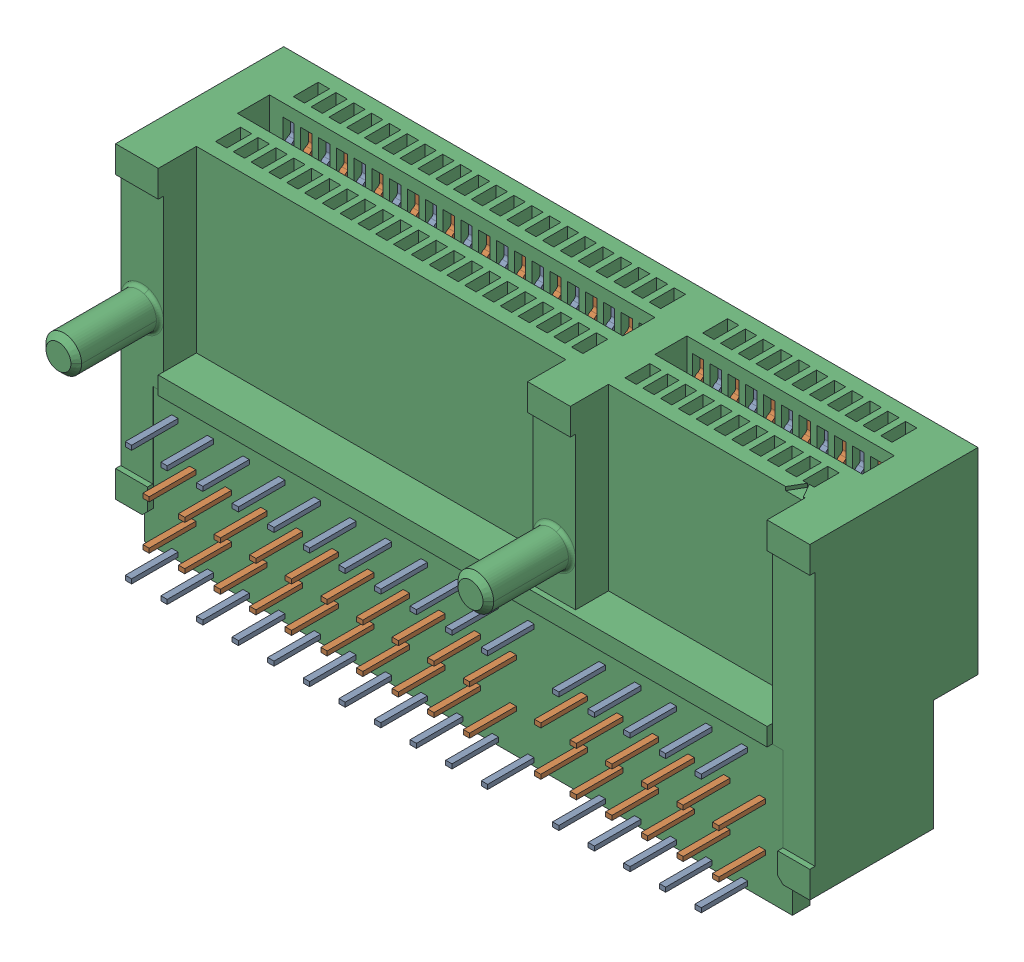
SolidWorks assembly PCIE_064_02_F_D_RA, configuration Default. Lengths in mm.
Overall size (39.03 18.85 13.86).
3 component instances, 3 part files, 0 mates.
Components (placement in the parent):
- PCIE_064_02_F_D_RA_3-1: PCIE_064_02_F_D_RA_3 [Default] at (6.9945 0 0) size (34 17.93 10.46)
- PCIE_064_02_F_D_RA_5-1: PCIE_064_02_F_D_RA_5 [Default] at (6.9945 0 0) size (34 16.93 10.48)
- PCIE_064_02_F_D_RA_7-1: PCIE_064_02_F_D_RA_7 [Default] at origin size (39.03 18.85 13.86)
